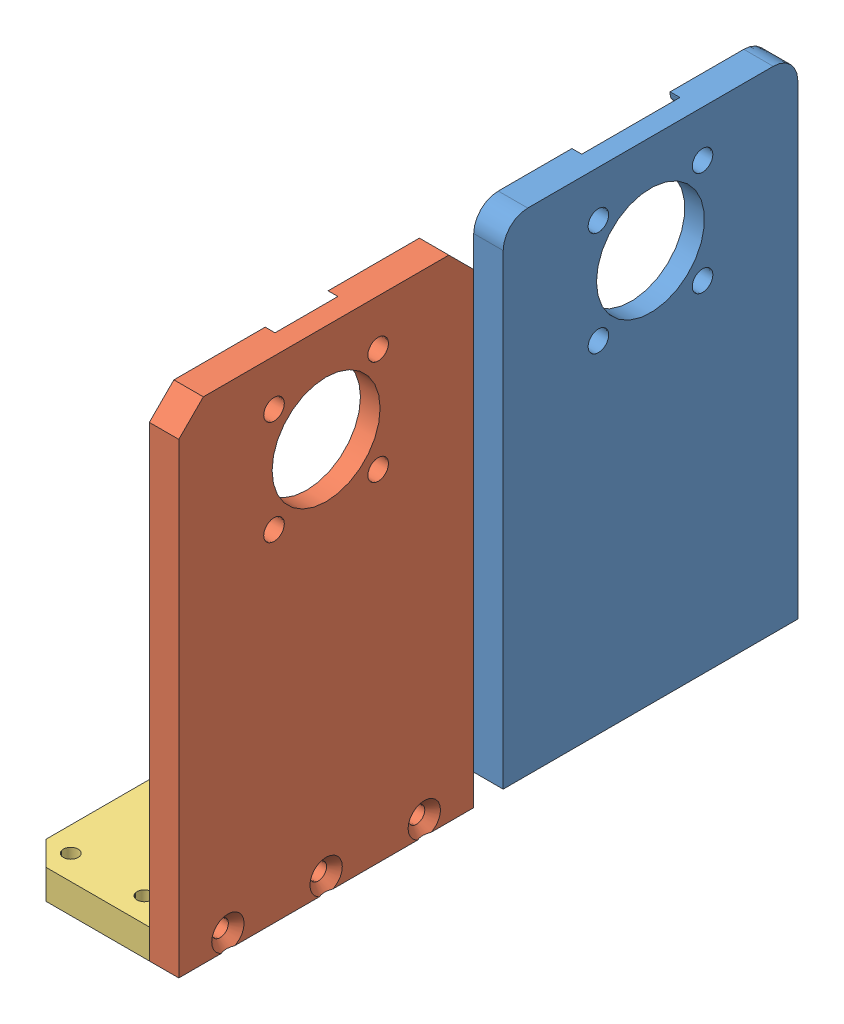
SolidWorks assembly 1, configuration 默认. Lengths in mm.
Overall size (32.22 100.34 125.99).
5 component instances, 3 part files, 12 mates.
Components (placement in the parent):
- 零件11-1: 零件11 [默认] at (-31.7538 8.8509 -30) size (32 100 60)
- XY 方向固定板-1: XY 方向固定板 [默认] at (-9.7538 9.35 0) x (0 1 0) z (-1 0 0) size (100 60 6.22) (hidden)
- XY 方向固定板2-1: XY 方向固定板2 [默认] at (-34.7538 -34.65 0) x (1 0 0) z (0 -1 0) size (26 60 6) (hidden)
- XY 方向固定板-2: XY 方向固定板 [默认] at (-15.8217 9.0144 65.9949) x (0 1 0) z (-1 0 0) size (100 60 6.22)
- XY 方向固定板2-2: XY 方向固定板2 [默认] at (-34.8217 -40.9856 65.9949) x (1 0 0) z (0 1 0) size (26 60 6)
Mates (geometry in assembly coordinates):
- 重合1: coincident anti-aligned: plane of 零件11-1 through (-15.7538 -40.65 30) normal (1 0 0); plane of XY 方向固定板-1 through (-15.7538 9.35 0) normal (-1 0 0)
- 重合2: coincident aligned: plane of 零件11-1 through (-31.7538 8.8509 -30) normal (0 0 -1); plane of XY 方向固定板-1 through (-15.7538 59.35 -30) normal (0 0 -1)
- 重合3: coincident aligned: plane of 零件11-1 through (-31.7538 8.8509 30) normal (0 0 1); plane of XY 方向固定板-1 through (-15.7538 59.35 30) normal (0 0 1)
- 重合4: coincident aligned: plane of 零件11-1 through (-47.7538 -40.65 30) normal (0 -1 0); plane of XY 方向固定板-1 through (-15.7538 -40.65 30) normal (0 -1 0)
- 重合5: coincident aligned: plane of XY 方向固定板-1 through (-15.7538 -40.65 30) normal (0 -1 0); plane of XY 方向固定板2-1 through (-34.7538 -40.65 0) normal (0 -1 0)
- 重合6: coincident aligned: plane of 零件11-1 through (-47.7538 -34.65 30) normal (-1 0 0); plane of XY 方向固定板2-1 through (-47.7538 -40.65 -30) normal (-1 0 0)
- 重合7: coincident aligned: plane of XY 方向固定板-1 through (-15.7538 59.35 -30) normal (0 0 -1); plane of XY 方向固定板2-1 through (-21.7538 -40.65 -30) normal (0 0 -1)
- 重合8: coincident anti-aligned: plane of XY 方向固定板-2 through (-21.8217 9.0144 65.9949) normal (-1 0 0); plane of XY 方向固定板2-2 through (-21.8217 -34.9856 95.9949) normal (1 0 0)
- 重合9: coincident aligned: plane of XY 方向固定板-2 through (-21.8217 -40.9856 95.9949) normal (0 -1 0); plane of XY 方向固定板2-2 through (-34.8217 -40.9856 65.9949) normal (0 -1 0)
- 重合10: coincident aligned: plane of XY 方向固定板-2 through (-21.8217 59.0144 95.9949) normal (0 0 1); plane of XY 方向固定板2-2 through (-21.8217 -34.9856 95.9949) normal (0 0 1)
- 平行1: parallel anti-aligned: plane of 零件11-1 through (-31.7538 8.8509 30) normal (0 0 1); plane of XY 方向固定板-2 through (-21.8217 59.0144 35.9949) normal (0 0 -1)
- 平行2: parallel aligned: plane of 零件11-1 through (-21.7538 -34.65 30) normal (0 1 0); plane of XY 方向固定板2-2 through (-34.8217 -34.9856 65.9949) normal (0 1 0)
